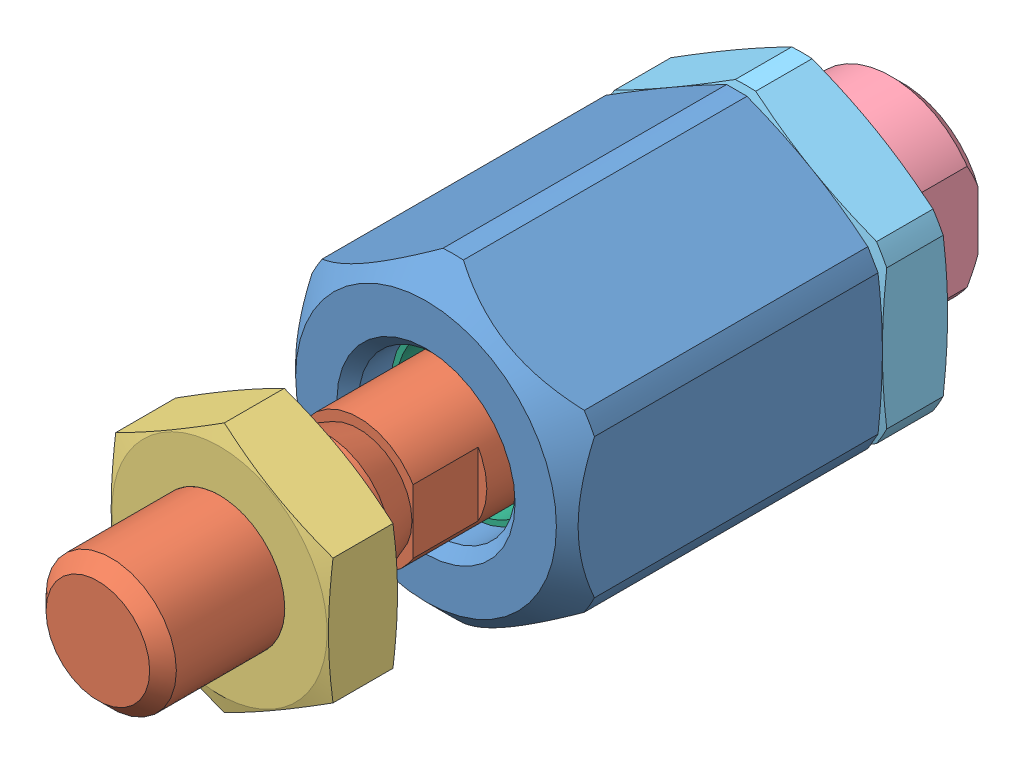
SolidWorks assembly 2061_FK_M6____asm_0_0_, configuration Standard. Lengths in mm.
Overall size (13 15.67 37).
7 component instances, 6 part files, 12 mates.
Components (placement in the parent):
- 2061_FK_M6____GE_-1: 2061_FK_M6____GE_ [Standard] at origin size (13 15.67 14.5)
- 2061_FK_M6____0BO_-1: 2061_FK_M6____0BO_ [Standard] at (0 0 3.1) x (-1 0 0) z (0 0 1) size (8 8 24.5)
- DIN_439_B___M6_F_-1: DIN_439_B___M6_F_ [Standard] at (0 0 6.3) x (1 0 0) z (0 1 0) size (10 3.2 11.55)
- 2061_FK_M6____BU_-1: 2061_FK_M6____BU_ [Standard] at (0 0 -10.4) x (1 0 0) z (0 0 -1) size (10 10 11.5)
- 2061_FK_M6____MU_-1: 2061_FK_M6____MU_ [Standard] at (0 0 -17.5) size (13 14.5 3)
- 2061_FK_M6____KG_-1: 2061_FK_M6____KG_ [Standard] at (0 0 -4) size (8.8 8.8 2)
- 2061_FK_M6____KG_-2: 2061_FK_M6____KG_ [Standard] at (0 0 -8.4) x (1 0 0) z (0 0 -1) size (8.8 8.8 2)
Mates (geometry in assembly coordinates):
- Deckungsgleich1: coincident: plane of 2061_FK_M6____GE_-1 through (0 0 0) normal (1 0 0); plane of 2061_FK_M6____0BO_-1
- Deckungsgleich2: coincident: line of 2061_FK_M6____GE_-1 through (80.9 0 -6.2) axis (-1 0 0); line of 2061_FK_M6____0BO_-1 through (-80.9 0 -6.2) axis (1 0 0)
- Deckungsgleich3: coincident: line of 2061_FK_M6____0BO_-1 through (0 0 84) axis (0 0 -1); line of DIN_439_B___M6_F_-1 through (0 0 -43.7) axis (0 0 1)
- Abstand1: distance = 0 mm: plane of 2061_FK_M6____BU_-1 through (0 0 -21.9) normal (0 0 -1); plane of 2061_FK_M6____GE_-1 through (0 0 -21.9) normal (0 0 1)
- Deckungsgleich4: coincident: line of 2061_FK_M6____GE_-1 through (0 0 80.9) axis (0 0 -1); line of 2061_FK_M6____BU_-1 through (0 0 -91.3) axis (0 0 1)
- Winkel3: planar angle = 0 rad: plane of 2061_FK_M6____BU_-1; plane of 2061_FK_M6____GE_-1 through (0 0 0) normal (1 0 0)
- Deckungsgleich6: coincident: plane of 2061_FK_M6____GE_-1 through (0 0 -17.5) normal (0 0 1); plane of 2061_FK_M6____MU_-1 through (0 0 -17.5) normal (0 0 1)
- Deckungsgleich7: coincident: line of 2061_FK_M6____GE_-1 through (0 0 80.9) axis (0 0 -1); line of 2061_FK_M6____MU_-1 through (0 0 63.4) axis (0 0 -1)
- Deckungsgleich9: coincident: plane of 2061_FK_M6____GE_-1 through (0 0 -2) normal (0 0 1); plane of 2061_FK_M6____KG_-1 through (0 0 -2) normal (0 0 1)
- Deckungsgleich10: coincident: line of 2061_FK_M6____GE_-1 through (0 0 80.9) axis (0 0 -1); line of 2061_FK_M6____KG_-1 through (0 0 76.9) axis (0 0 -1)
- Deckungsgleich11: coincident: plane of 2061_FK_M6____GE_-1 through (0 0 -10.4) normal (0 0 1); plane of 2061_FK_M6____KG_-2 through (0 0 -10.4) normal (0 0 -1)
- Deckungsgleich12: coincident: line of 2061_FK_M6____GE_-1 through (0 0 80.9) axis (0 0 -1); line of 2061_FK_M6____KG_-2 through (0 0 -89.3) axis (0 0 1)
